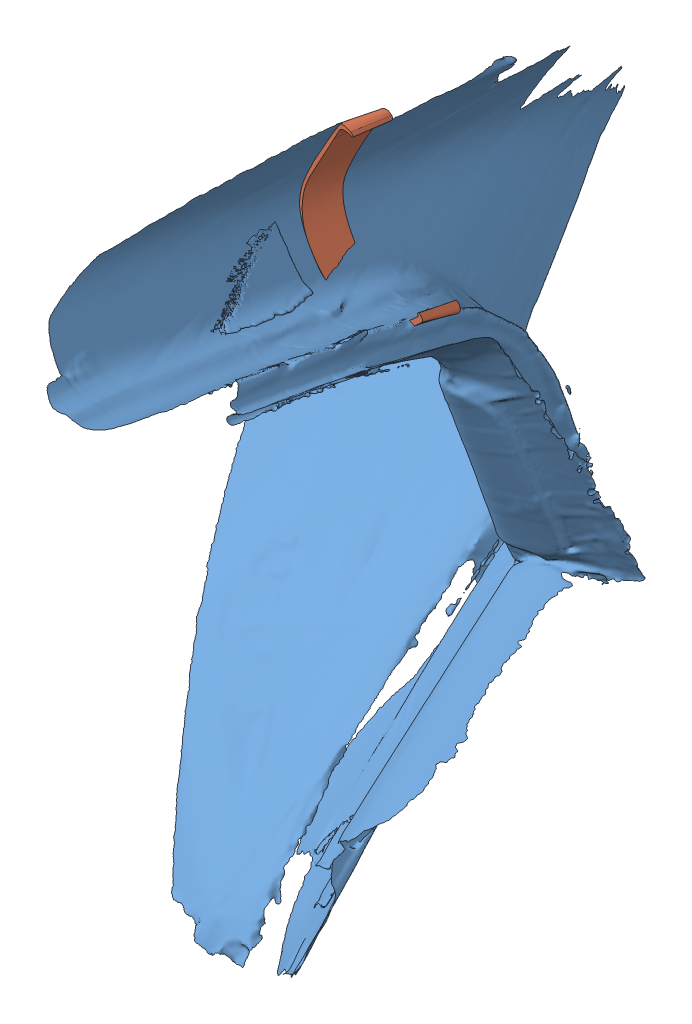
SolidWorks assembly focus_a, configuration Default. Lengths in mm.
Overall size (276.78 370.21 467.74).
2 component instances, 2 part files, 0 mates.
Components (placement in the parent):
- focus_a-1: focus_a [Default] at (198.1073 265.0512 617.9692) size (276.78 370.21 467.74)
- focus_a_a_clear-1: focus_a_a_clear [默认] at (192.1943 249.5379 576.6602) size (81.46 108.21 30.22)
